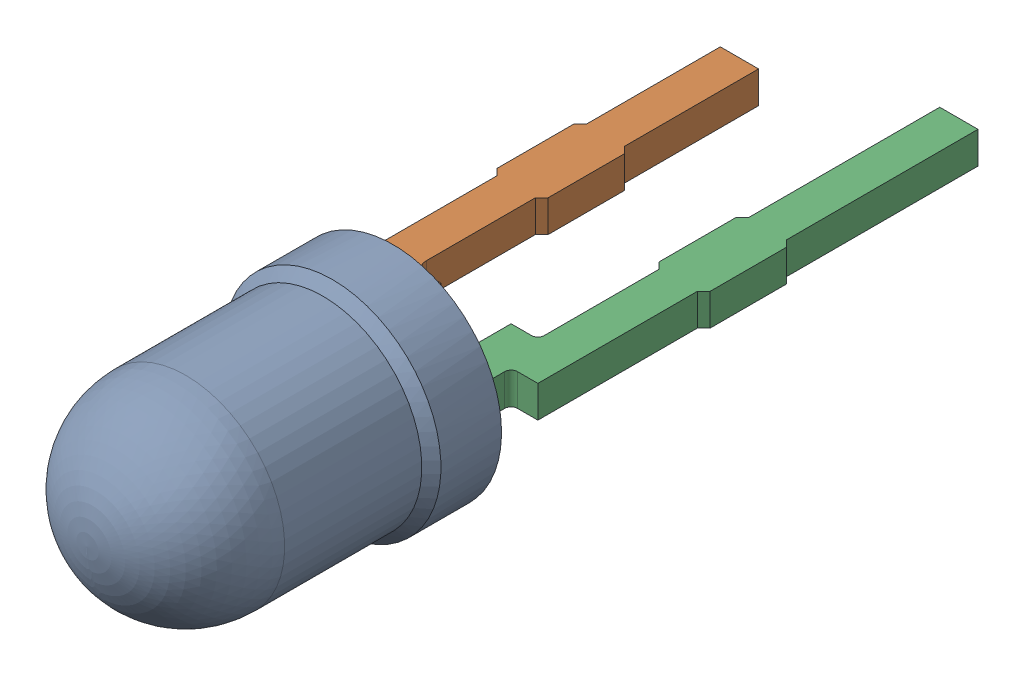
SolidWorks assembly User_Library-LA_3366_sc, configuration Default. Lengths in mm.
Overall size (3.4 3.4 12.4).
3 component instances, 3 part files, 0 mates.
Components (placement in the parent):
- User_Library-LA_3366_sc_BODY_amber-1: User_Library-LA_3366_sc_BODY_amber [Default] x (1 0 0) z (0 -1 0) size (3.4 4.8 3.4)
- User_Library-LA_3366_sc_LEAD_A_sc-1: User_Library-LA_3366_sc_LEAD_A_sc [Default] at (0 0.25 0) x (1 0 0) z (0 -1 0) size (1.12 6.7 0.5)
- User_Library-LA_3366_sc_LEAD_K_sc-1: User_Library-LA_3366_sc_LEAD_K_sc [Default] at (0 -0.25 0) x (-1 0 0) z (0 1 0) size (1.12 7.6 0.5)
